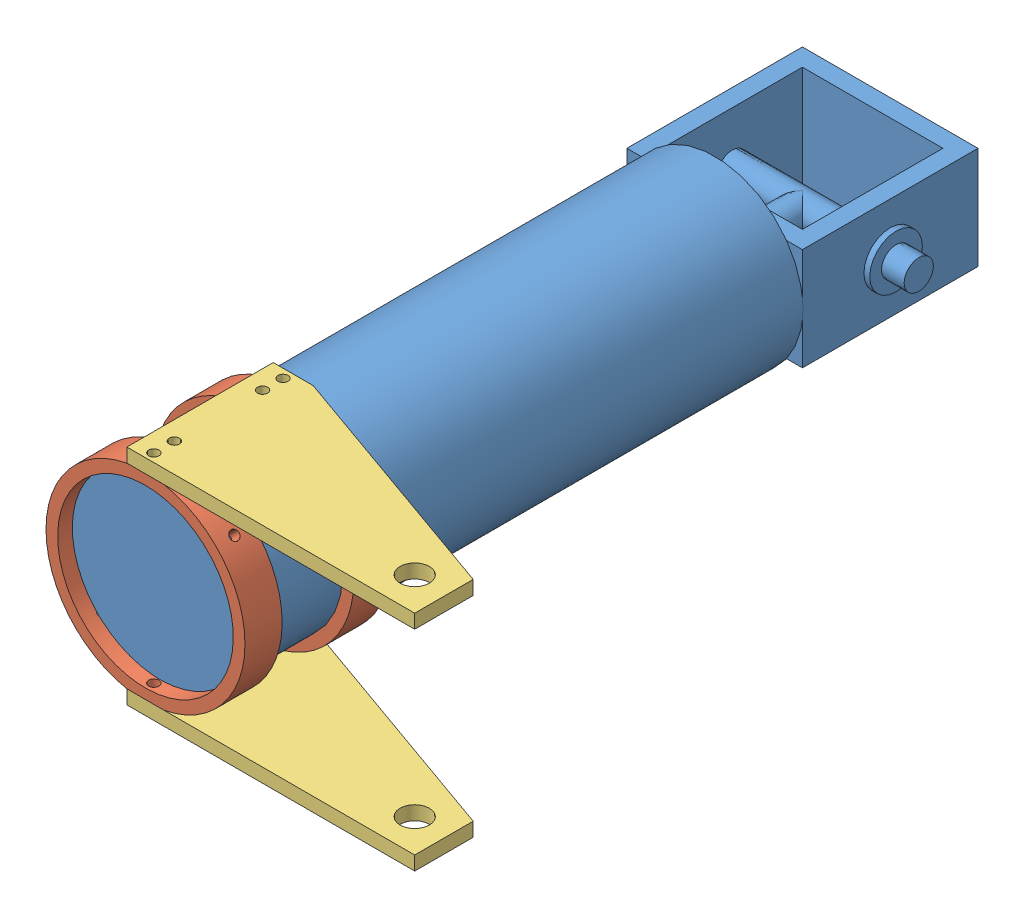
SolidWorks assembly EslabonVertical_Inv, configuration Predeterminado. Lengths in mm.
Overall size (140.08 96.17 254.5).
5 component instances, 3 part files, 11 mates.
Components (placement in the parent):
- EslabonSimplificado-1: EslabonSimplificado [Predeterminado] at origin size (79.5 60.33 249.5)
- SujeccionMotorV2-1: SujeccionMotorV2 [Predeterminado] at (0 0 181) x (0.707107 -0.707107 0) z (0 0 1) size (68 68 12.7)
- Soporte-1: Soporte [Predeterminado] at (-6.35 -33.4018 224.5) x (0 0 1) z (0 -1 0) size (50 98.35 4.76)
- SujeccionMotorV2-2: SujeccionMotorV2 [Predeterminado] at (0 0 218.15) x (0.707107 -0.707107 0) z (0 0 1) size (68 68 12.7)
- Soporte-2: Soporte [Predeterminado] at (-6.35 38.1643 224.5) x (0 0 1) z (0 -1 0) size (50 98.35 4.76)
Mates (geometry in assembly coordinates):
- Concéntrica2: concentric aligned: cylinder of EslabonSimplificado-1 through (0 0 30) axis (0 0 1) radius 30.165; cylinder of SujeccionMotorV2-2 through (0 0 211.8) axis (0 0 1) radius 30
- Concéntrica3: concentric aligned: cylinder of EslabonSimplificado-1 through (0 0 30) axis (0 0 1) radius 30.165; cylinder of SujeccionMotorV2-1 through (0 0 174.65) axis (0 0 1) radius 30
- Paralelo2: parallel aligned: plane of EslabonSimplificado-1 through (0 -17.5 0) normal (0 -1 0); plane of SujeccionMotorV2-1 through (6.35 -33.4018 174.65) normal (0 -1 0)
- Paralelo3: parallel aligned: plane of SujeccionMotorV2-1 through (6.35 -33.4018 174.65) normal (0 -1 0); plane of SujeccionMotorV2-2 through (6.35 -33.4018 211.8) normal (0 -1 0)
- Distancia1: distance = 5 mm aligned: plane of EslabonSimplificado-1 through (0 0 219.5) normal (0 0 1); plane of SujeccionMotorV2-2 through (0 0 224.5) normal (0 0 1)
- Coincidente1: coincident anti-aligned: plane of SujeccionMotorV2-1 through (6.35 -33.4018 174.65) normal (0 -1 0); plane of Soporte-1 through (-6.35 -33.4018 224.5) normal (0 1 0)
- Concéntrica4: concentric aligned: cylinder of SujeccionMotorV2-1 through (0 -48.0833 177.5) axis (0 1 0) radius 1.75; cylinder of Soporte-1 through (0 -38.1643 177.5) axis (0 1 0) radius 1.75
- Concéntrica5: concentric aligned: cylinder of Soporte-1 through (0 -38.1643 221.65) axis (0 1 0) radius 1.75; cylinder of SujeccionMotorV2-2 through (0 -48.0833 221.65) axis (0 1 0) radius 1.75
- Coincidente3: coincident: plane of SujeccionMotorV2-2 through (6.35 33.4018 211.8) normal (0 1 0); plane of Soporte-2 through (-6.8831 33.4018 222.6831) normal (0 -1 0)
- Concéntrica6: concentric: cylinder of SujeccionMotorV2-2 through (0 -48.0833 221.65) axis (0 1 0) radius 1.75; cylinder of Soporte-2 through (0 33.4018 221.65) axis (0 1 0) radius 1.75
- Concéntrica7: concentric aligned: cylinder of SujeccionMotorV2-1 through (0 -48.0833 177.5) axis (0 1 0) radius 1.75; cylinder of Soporte-2 through (11.8993 33.4018 179.1338) axis (0 1 0) radius 1.75
